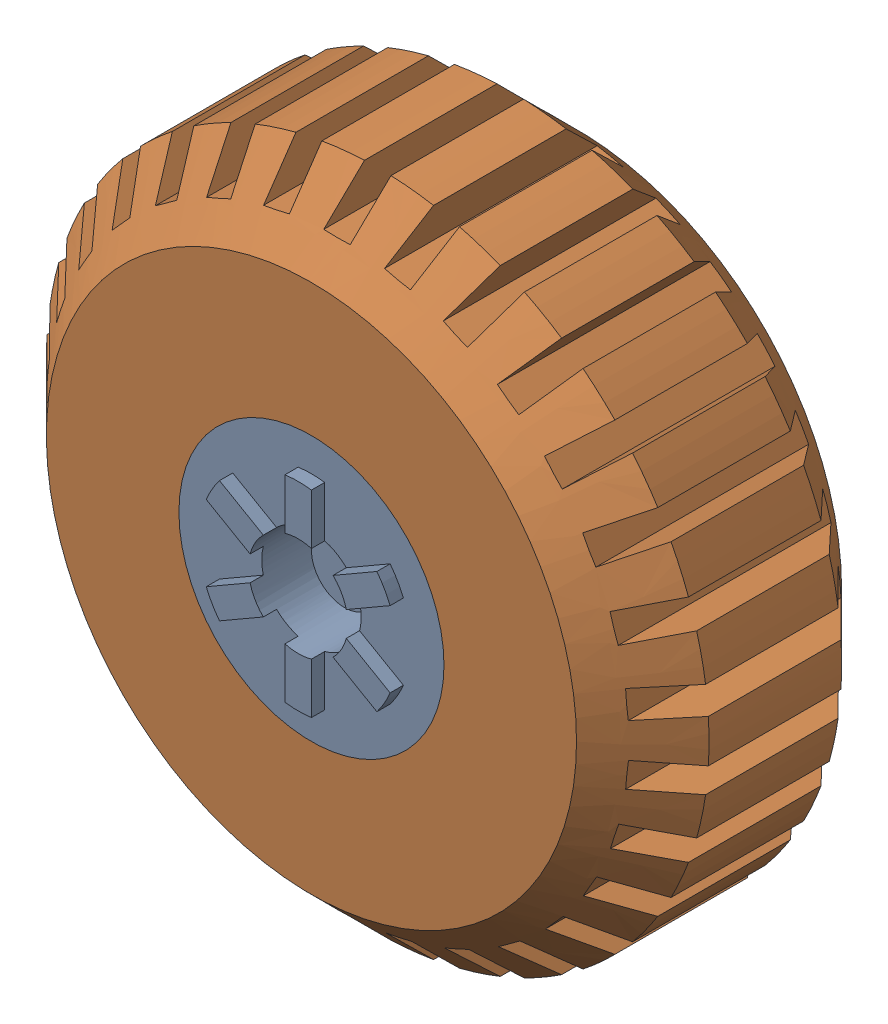
SolidWorks assembly jeep tyre assem 1, configuration Default. Lengths in mm.
Overall size (100 99.92 42).
2 component instances, 2 part files, 3 mates.
Components (placement in the parent):
- jeep rim..-1: jeep rim.. [Default] at (-10.5098 2.7608 -17.3298) size (40 40 42)
- jeep tyre 1-1: jeep tyre 1 [Default] at (-11.3405 2.7608 -17.3298) size (100 99.92 40)
Mates (geometry in assembly coordinates):
- Coincident1: coincident: plane of jeep rim..-1 through (-10.5098 2.7608 22.6702) normal (0 0 1); plane of jeep tyre..-1 through (-10.5098 2.7608 22.6702) normal (0 0 1)
- Concentric1: concentric: cylinder of jeep rim..-1 through (-10.5098 2.7608 22.6702) axis (0 0 -1) radius 20; cylinder of jeep tyre..-1 through (-10.5098 2.7608 22.6702) axis (0 0 -1) radius 20
- Coincident2: coincident: plane of jeep rim..-1 through (-10.5098 2.7608 22.6702) normal (0 0 1); plane of jeep tyre..-1 through (-10.5098 2.7608 22.6702) normal (0 0 1)
